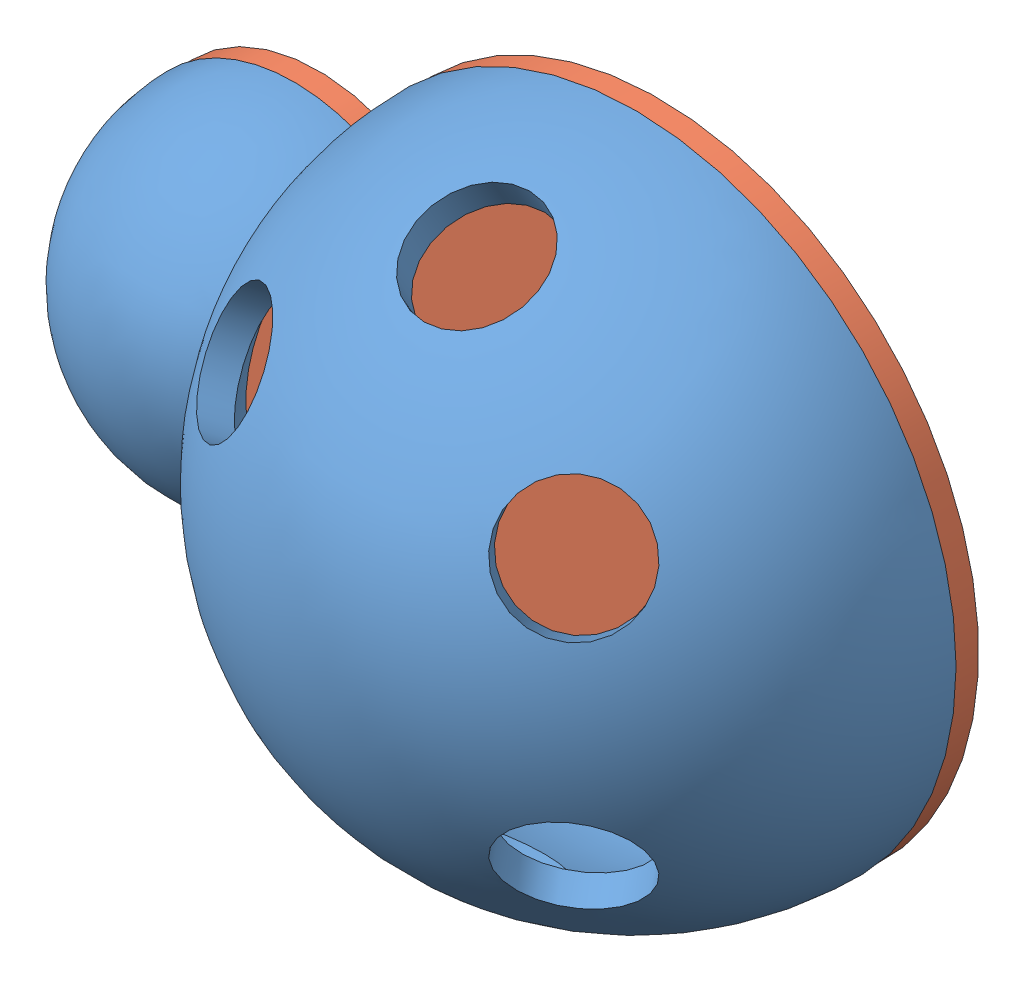
SolidWorks assembly LadeeBugFinally, configuration Default. Lengths in mm.
Overall size (187.74 150.24 120.12).
2 component instances, 2 part files, 1 mates.
Components (placement in the parent):
- LadeeBug-1: LadeeBug [Default] at (30.8467 93.5515 167.3635) size (187.4 150.24 120.12)
- LadeeBugbottom-1: LadeeBugbottom [Default] at (30.7735 93.3651 162.3635) x (1 0 0) z (0 -1 0) size (171.4 6 131.4)
Mates (geometry in assembly coordinates):
- Coincident1: coincident anti-aligned: plane of LadeeBug-1 through (-39.1533 93.5515 167.3635) normal (0 0 -1); plane of LadeeBugbottom-1 through (-4.2265 93.3651 167.3635) normal (0 0 1)
